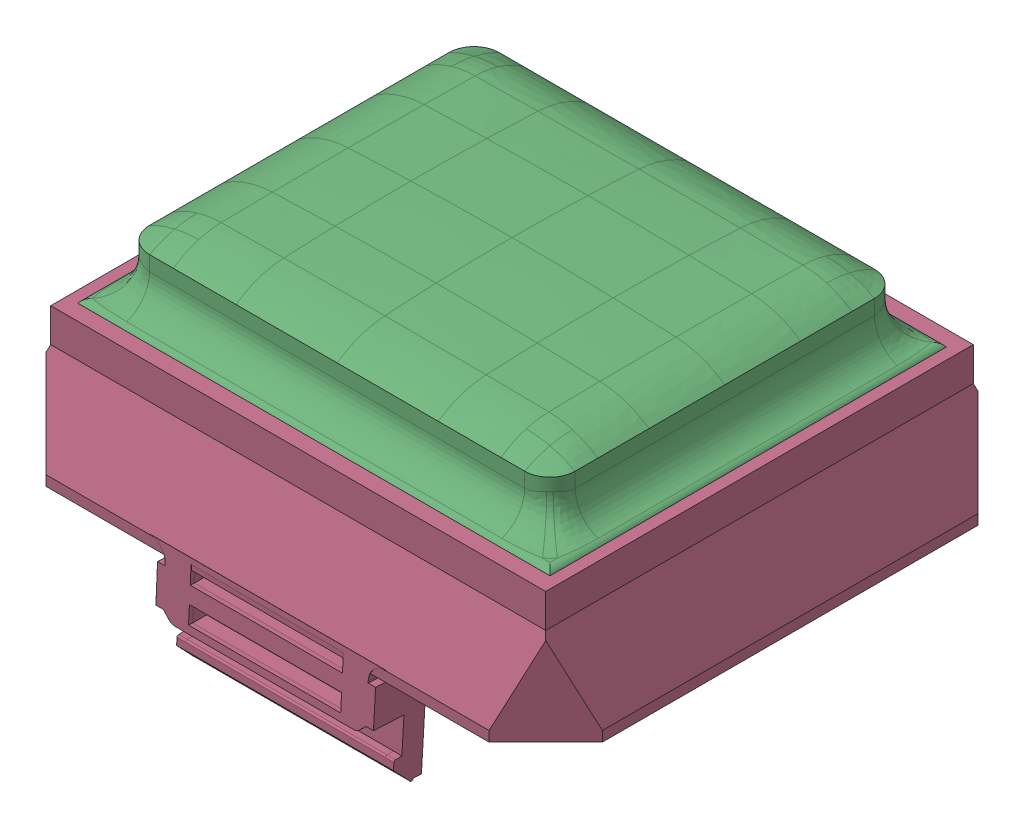
SolidWorks assembly Dot1, configuration 默认. Lengths in mm.
Overall size (33 18.27 29.5).
5 component instances, 5 part files, 18 mates.
Components (placement in the parent):
- Lens-1: Dot1Lens [默认] at origin size (28.33 2.18 23.83)
- InsideSkin-1: Dot1InsideSkin [默认] at (0.0001 0 0.2499) size (23.8 5.48 19.29)
- Topskin-1: Dot1Topskin [默认] at (0.0001 2 0.2499) size (28.02 6.25 23.52)
- Supportbase-2: Dot1Supportbase [默认] at origin size (33 14.02 29.5)
- Dor-1: Dot1Dor [默认] at (-1.2499 23.9 -0.9614) x (-1 0 0) z (0 -1 0) size (18.98 16.99 1.63)
Mates (geometry in assembly coordinates):
- 同心2: concentric anti-aligned: cylinder of InsideSkin-1 through (10.8751 17.7531 8.6249) axis (0 1 0) radius 0.7; cylinder of Board3Con1612611OriginalSkin_TOP-1 through (10.8751 24 8.6249) axis (0 -1 0) radius 0.7
- 同心3: concentric anti-aligned: cylinder of InsideSkin-1 through (10.8751 17.7531 -9.1251) axis (0 1 0) radius 0.7; cylinder of Board3Con1612611OriginalSkin_TOP-1 through (10.8751 24 -9.1251) axis (0 -1 0) radius 0.7
- 重合4: coincident aligned: plane of InsideSkin-1 through (10.8751 19 -9.1251) normal (0 -1 0); plane of Board3Con1612611OriginalSkin_TOP-1 through (0.0001 19 0.2499) normal (0 -1 0)
- 重合6: coordinate: point of NewContiSupportBase-2
- 重合7: coincident anti-aligned: plane of lensall-1 through (13.75 19 -11.5) normal (0.939693 0.34202 0); plane of NewContiSupportBase-2 through (13.75 19 12.7803) normal (-0.939693 -0.34202 0)
- 同心5: concentric aligned: cylinder of lensall-1 through (13.3294 18.6938 -11.0794) axis (-0.323616 0.889126 0.323616) radius 0.5; cylinder of NewContiSupportBase-2 through (10.7866 25.6801 -8.5366) axis (-0.323616 0.889126 0.323616) radius 0.5
- 重合8: coincident anti-aligned: plane of lensall-1 through (0 18 0) normal (0 -1 0); plane of NewContiSupportBase-2 through (0 18 0) normal (0 1 0)
- 重合9: coincident anti-aligned: plane of lensall-1 through (0 19 0) normal (0 1 0); plane of Board3Con1612611OriginalSkin_TOP-1 through (0.0001 19 0.2499) normal (0 -1 0)
- 重合10: coincident anti-aligned: plane of Board3Con1612611OriginalSkin_TOP-1 through (0.0001 19 11.7499) normal (0 0 1); plane of NewContiSupportBase-2 through (-13.5999 21 11.7499) normal (0 0 -1)
- 重合11: coincident anti-aligned: plane of Board3Con1612611OriginalSkin_TOP-1 through (14.0001 19 0.2499) normal (1 0 0); plane of NewContiSupportBase-2 through (14.0001 21 11.7499) normal (-1 0 0)
- 平行1: parallel: plane of InsideSkin-1 through (-11.3749 17.7531 9.3249) normal (0 0 1); line of Dor-1 through (8.7251 23.9 6.9749) axis (-1 0 0)
- 平行2: parallel: plane of InsideSkin-1 through (-12.0749 17.7531 -9.1251) normal (-1 0 0); line of Dor-1 through (-12.2749 23.9 -8.0251) axis (0 0 1)
- 距离1: distance = 1.8 mm: line of Dor-1 through (8.7251 23.9 -8.0251) axis (-1 0 0); plane of InsideSkin-1 through (-11.3749 17.7531 -9.8251) normal (0 0 -1)
- 平行3: parallel anti-aligned: line of Supportbase-2 through (14.6801 19 12.1801) axis (0 0 -1); line of Dor-1 through (9.9597 23.9 -9.2955) axis (0 0 1)
- 距离2: distance = 5 mm: plane of Lens-1 through (0 19 0) normal (0 1 0); line of Dor-1 through (-10.7499 26.3155 -7.7501) axis (0 0 1)
- 距离3: distance = 2.85 mm: plane of InsideSkin-1 through (11.5751 17.7531 -9.1251) normal (1 0 0); line of Dor-1 through (8.7251 23.9 -8.0251) axis (0 0 1)
- 平行4: parallel aligned: line of Supportbase-2 through (14.1801 19 -12.6801) axis (-1 0 0); line of Dor-1 through (9.9597 23.9 10.7045) axis (-1 0 0)
- 距离5: distance = 4.9 mm: plane of Lens-1 through (0 19 0) normal (0 1 0); line of Dor-1 through (8.7251 23.9 -8.0251) axis (0 0 1)
